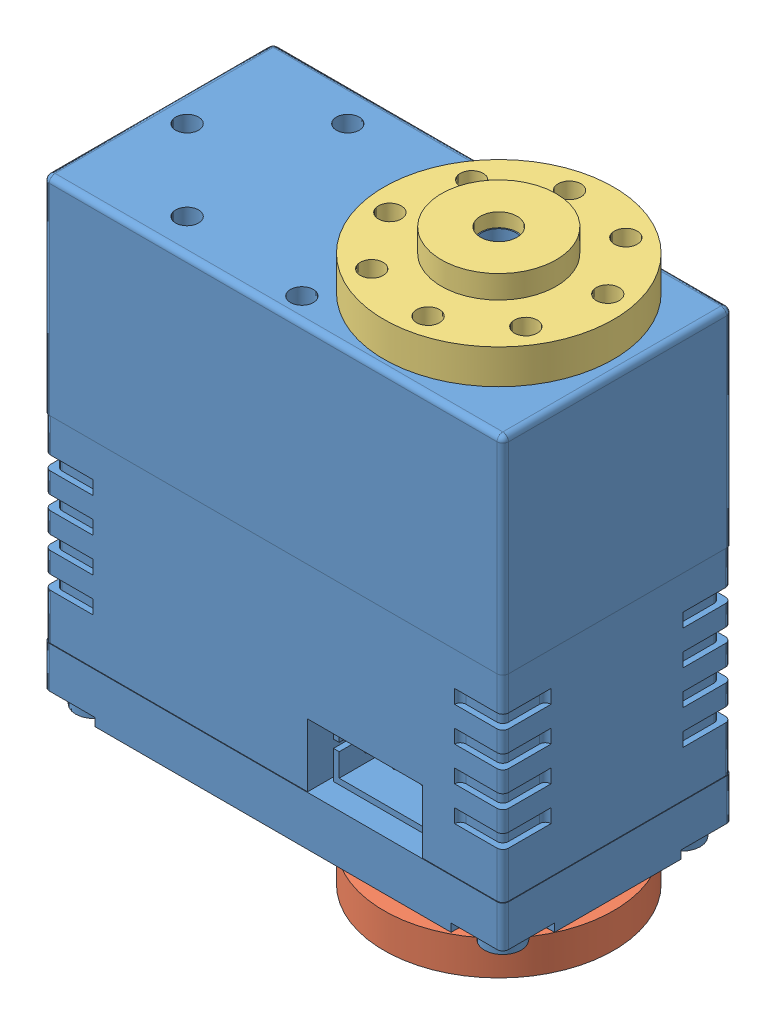
SolidWorks assembly 舵机, configuration 默认. Lengths in mm.
Overall size (43.48 52.6 27.66).
3 component instances, 3 part files, 4 mates.
Components (placement in the parent):
- 舵机-1: 舵机 [默认] at origin size (40 51.4 20)
- 副舵盘-1: 副舵盘 [默认] at (9.65 -0.8 0) x (-0.933258 0 -0.359207) z (-0.359207 0 0.933258) size (20 5 20)
- 主舵盘-1: 主舵盘 [默认] at (9.65 40.8 0) x (0.838844 0 0.544372) z (-0.544372 0 0.838844) size (20 5 20)
Mates (geometry in assembly coordinates):
- 重合3: coincident anti-aligned: plane of 舵机-1 through (9.65 -0.8 0) normal (0 -1 0); plane of 副舵盘-1 through (9.65 -0.8 0) normal (0 1 0)
- 同心1: concentric anti-aligned: circle of 舵机-1; circle of 副舵盘-1
- 重合4: coincident anti-aligned: plane of 舵机-1 through (9.65 40.8 0) normal (0 1 0); plane of 主舵盘-1 through (9.65 40.8 0) normal (0 -1 0)
- 同心2: concentric anti-aligned: circle of 舵机-1; circle of 主舵盘-1
